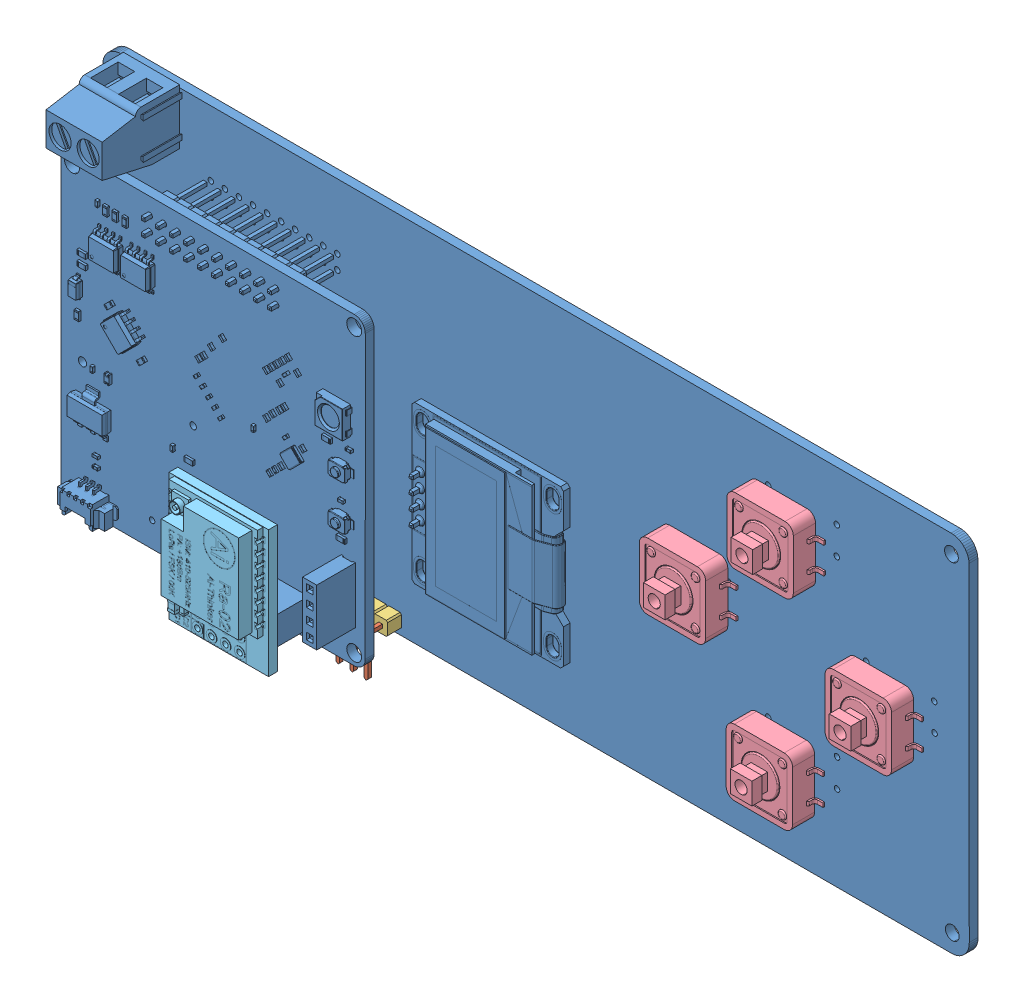
SolidWorks assembly Assemblage, configuration Défaut. Lengths in mm.
Overall size (156.59 71.23 29.71).
24 component instances, 5 part files, 8 mates.
Components (placement in the parent):
- test_board-1: test_board [Défaut] at (-201.5181 89.9617 -8.4806) size (156.59 66.26 22.21)
- Header 1 Pin-1: Header 1 Pin [Varsayılan] at (-89.3353 -48.622 -5.6843) x (-1 -0.000058 0) z (-0.000058 1 0) size (2.54 8.15 8.52)
  - Pin-1: Pin [Varsayılan] at (-2.2801 -0.4288 7.825) size (0.65 8.15 7.58)
  - Header_Body-1: Header_Body [Varsayılan] at (-2.2801 -1.2163 7.825) size (2.54 2.5 2.54)
- Header 1 Pin-3: Header 1 Pin [Varsayılan] at (-86.7953 -48.6222 -5.6843) x (-1 -0.000058 0) z (-0.000058 1 0) size (2.54 8.15 8.52)
  - Pin-1: Pin [Varsayılan] at (-2.2801 -0.4288 7.825) size (0.65 8.15 7.58)
  - Header_Body-1: Header_Body [Varsayılan] at (-2.2801 -1.2163 7.825) size (2.54 2.5 2.54)
- Header 1 Pin-4: Header 1 Pin [Varsayılan] at (-84.2553 -48.6224 -5.6843) x (-1 -0.000058 0) z (-0.000058 1 0) size (2.54 8.15 8.52)
  - Pin-1: Pin [Varsayılan] at (-2.2801 -0.4288 7.825) size (0.65 8.15 7.58)
  - Header_Body-1: Header_Body [Varsayılan] at (-2.2801 -1.2163 7.825) size (2.54 2.5 2.54)
- Big_pushbutton-1: Big_pushbutton [Défaut] at (-27.7215 -7.528 -6.9006) x (1 0.000058 0) z (0 0 1) size (15.6 12 7.3)
- Big_pushbutton-2: Big_pushbutton [Défaut] at (-8.2264 11.1312 -3.2506) size (15.6 12 7.3)
- Big_pushbutton-3: Big_pushbutton [Défaut] at (9.5088 -7.6498 -3.2506) size (15.6 12 7.3)
- Big_pushbutton-4: Big_pushbutton [Défaut] at (-8.3674 -25.1734 -3.2506) size (15.6 12 7.3)
- lora-1: lora [Défaut] at (-90.8897 -27.6846 -6.8944) size (18 23 7.5)
  - LoRa-Ra-02.step-1: LoRa-Ra-02.step [Défaut] at (-9.7377 -11.7085 20.5) size (18 23 5)
  - Header_Body-1: Header_Body [Varsayılan] at (-4.5984 -10.4385 20.5) x (1 0 0) z (0 1 0) size (2.54 2.5 2.54)
  - Header_Body-2: Header_Body [Varsayılan] at (-2.0284 -10.4385 20.5) x (1 0 0) z (0 1 0) size (2.54 2.5 2.54)
  - Header_Body-3: Header_Body [Varsayılan] at (0.5416 -10.4385 20.5) x (1 0 0) z (0 1 0) size (2.54 2.5 2.54)
  - Header_Body-4: Header_Body [Varsayılan] at (3.1116 -10.4385 20.5) x (1 0 0) z (0 1 0) size (2.54 2.5 2.54)
  - Header_Body-5: Header_Body [Varsayılan] at (3.1116 -7.8685 20.5) x (1 0 0) z (0 1 0) size (2.54 2.5 2.54)
  - Header_Body-6: Header_Body [Varsayılan] at (0.5416 -7.8685 20.5) x (1 0 0) z (0 1 0) size (2.54 2.5 2.54)
  - Header_Body-7: Header_Body [Varsayılan] at (-2.0284 -7.8685 20.5) x (1 0 0) z (0 1 0) size (2.54 2.5 2.54)
  - Header_Body-8: Header_Body [Varsayılan] at (-4.5984 -7.8685 20.5) x (1 0 0) z (0 1 0) size (2.54 2.5 2.54)
Mates (geometry in assembly coordinates):
- Coïncidente1: coincident: plane of test_board-1 through (-56.368 -10.2095 -6.9006) normal (0 0 1); plane of Header 1 Pin-1/Assemblage29^Header 1 Pin-1/Header_Body-1 through (-86.8328 -41.8109 -6.9006) normal (0 0 -1)
- Coïncidente2: coincident aligned: plane of test_board-1 through (18.8983 -43.0747 -8.4806) normal (0.000058 -1 0); plane of Header 1 Pin-1/Assemblage29^Header 1 Pin-1/Header_Body-1 through (-87.8527 -43.0809 -4.4006) normal (0.000058 -1 0)
- Coïncidente3: coincident anti-aligned: plane of test_board-1 through (-56.368 -10.2095 -6.9006) normal (0 0 1); plane of Header 1 Pin-1/Header_Body-1 through (-87.0557 -40.7969 -6.9006) normal (0 0 -1)
- Distance1: distance = 0.3 mm: cylinder of test_board-1 through (-87.0807 -40.7913 -9.2706) axis (0 0 1) radius 0.5; plane of Header 1 Pin-1/Pin-1 through (-87.3806 -41.3719 -2.6506) normal (-1 -0.000058 0)
- Verrouiller1: lock: unknown of test_board-1; unknown of Big_pushbutton-1
- Coïncidente12: coincident anti-aligned: plane of test_board-1 through (-99.2081 -39.3931 11.1056) normal (0 0 1); plane of lora-1/Header_Body-4 through (-87.7781 -38.1231 11.1056) normal (0 0 -1)
- Coïncidente13: coincident aligned: plane of test_board-1 through (-99.2081 -39.3931 4.1056) normal (0 -1 0); plane of lora-1/Header_Body-4 through (-86.7581 -39.3931 11.1056) normal (0 -1 0)
- Coïncidente14: coincident aligned: plane of test_board-1 through (-86.5081 -39.3931 4.1056) normal (1 0 0); plane of lora-1/Header_Body-4 through (-86.5081 -39.1431 11.1056) normal (1 0 0)
